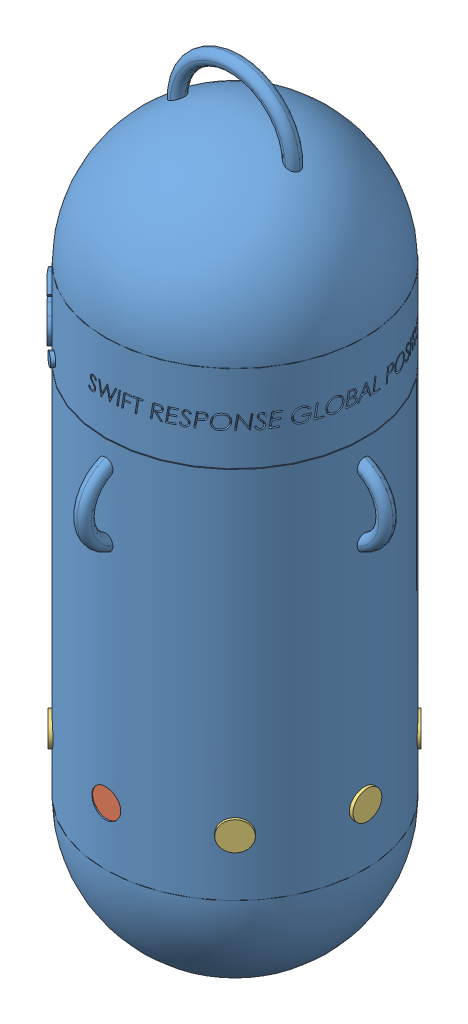
SolidWorks assembly Assembled Final, configuration Default. Lengths in mm.
Overall size (69.85 169.86 69.85).
9 component instances, 3 part files, 8 mates.
Components (placement in the parent):
- Production Ready Model-1: Production Ready Model [Default] at origin size (69.85 169.86 69.85)
- Speaker-1: Speaker [Default] at (0 12.7 27.462) x (0.789136 0.614218 0) z (0 0 1) size (6.35 6.35 0.79)
- Speaker-2: Speaker [Default] at (0 12.7 -28.2462) x (0.810032 0.586386 0) z (0 0 1) size (6.35 6.35 0.79)
- LED-1: LED [Default] at (-20.691 12.7 -20.691) x (-0.333684 -0.881652 0.333684) z (0.707107 0 0.707107) size (6.35 6.35 1.59)
- LED-2: LED [Default] at (19.4741 12.7 19.4741) x (0.638652 0.429241 -0.638652) z (0.707107 0 0.707107) size (6.35 6.35 1.59)
- LED-3: LED [Default] at (-28.9868 12.7 0) x (0 -0.913152 -0.407618) z (1 0 0) size (6.35 6.35 1.59)
- LED-4: LED [Default] at (29.2014 12.7 0) x (0 -0.873524 0.486782) z (-1 0 0) size (6.35 6.35 1.59)
- LED-5: LED [Default] at (20.5355 12.7 -20.5355) x (0.490009 -0.72096 0.490009) z (-0.707107 0 0.707107) size (6.35 6.35 1.59)
- LED-6: LED [Default] at (-19.5353 12.7 19.5353) x (0.706564 -0.039182 0.706564) z (-0.707107 0 0.707107) size (6.35 6.35 1.59)
Mates (geometry in assembly coordinates):
- Concentric1: concentric aligned: cylinder of Production Ready Model-1 through (0 12.7 28.575) axis (0 0 -1) radius 3.175; cylinder of Speaker-1 through (0 12.7 28.2558) axis (0 0 -1) radius 3.175
- Concentric2: concentric anti-aligned: cylinder of Production Ready Model-1 through (0 12.7 -28.575) axis (0 0 1) radius 3.175; cylinder of Speaker-2 through (0 12.7 -27.4525) axis (0 0 -1) radius 3.175
- Concentric3: concentric anti-aligned: cylinder of Production Ready Model-1 through (20.2056 12.7 -20.2056) axis (-0.707107 0 0.707107) radius 3.175; cylinder of LED-5 through (19.4129 12.7 -19.4129) axis (0.707107 0 -0.707107) radius 3.175
- Concentric4: concentric anti-aligned: cylinder of Production Ready Model-1 through (-20.2056 12.7 -20.2056) axis (0.707107 0 0.707107) radius 3.175; cylinder of LED-1 through (-19.5685 12.7 -19.5685) axis (-0.707107 0 -0.707107) radius 3.175
- Concentric5: concentric anti-aligned: cylinder of Production Ready Model-1 through (28.575 12.7 0) axis (-1 0 0) radius 3.175; cylinder of LED-4 through (27.6139 12.7 0) axis (1 0 0) radius 3.175
- Concentric6: concentric aligned: cylinder of Production Ready Model-1 through (20.2056 12.7 20.2056) axis (-0.707107 0 -0.707107) radius 3.175; cylinder of LED-2 through (20.5966 12.7 20.5966) axis (-0.707107 0 -0.707107) radius 3.175
- Concentric7: concentric aligned: cylinder of Production Ready Model-1 through (-20.2056 12.7 20.2056) axis (0.707107 0 -0.707107) radius 3.175; cylinder of LED-6 through (-20.6578 12.7 20.6578) axis (0.707107 0 -0.707107) radius 3.175
- Concentric8: concentric anti-aligned: cylinder of Production Ready Model-1 through (-28.575 12.7 0) axis (1 0 0) radius 3.175; cylinder of LED-3 through (-27.3993 12.7 0) axis (-1 0 0) radius 3.175
